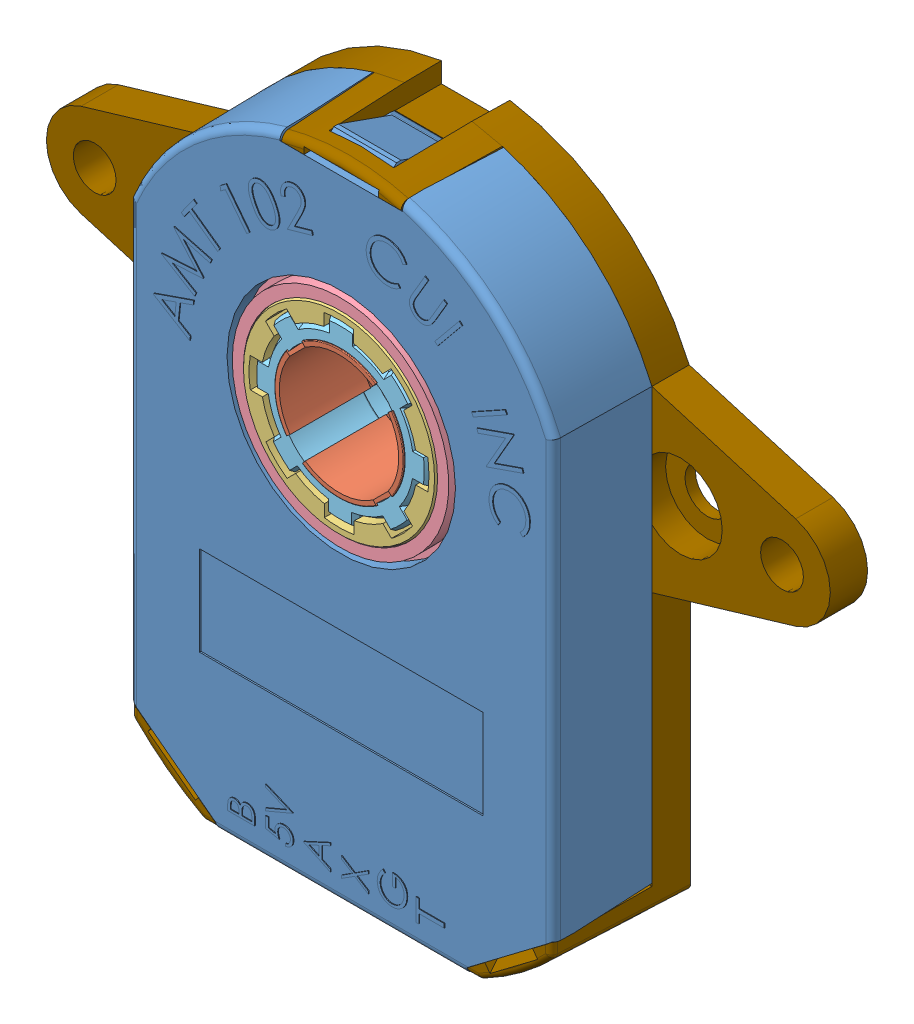
SolidWorks assembly MR2_planetary_shoulder_CUI_INC_cui_amt102-0048-n8000-w, configuration Default. Lengths in mm.
Overall size (52.5 46.23 9.15).
9 component instances, 9 part files, 0 mates.
Components (placement in the parent):
- MR2_planetary_shoulder_CUI_INC_amt-102-top-cover-rev-h-1: MR2_planetary_shoulder_CUI_INC_amt-102-top-cover-rev-h [Default] at (0 0 5.23) x (-1 0 0) z (0 0 -1) size (28.6 43.26 6.55)
- MR2_planetary_shoulder_CUI_INC_amt-sleeve-rev-d(8 mm)-1: MR2_planetary_shoulder_CUI_INC_amt-sleeve-rev-d(8 mm) [Default] at (0 0 -2.42) x (0.999996 0.002864 0) z (0 0 1) size (10.79 10.79 7.8)
- MR2_planetary_shoulder_CUI_INC_amt-hub-top-rev-d1-1: MR2_planetary_shoulder_CUI_INC_amt-hub-top-rev-d1 [Default] at (0 0 2.13) x (0.999996 0.002864 0) z (0 0 1) size (14 14 5.67)
- MR2_planetary_shoulder_CUI_INC_amt-hub-bottom-rev-b-1: MR2_planetary_shoulder_CUI_INC_amt-hub-bottom-rev-b [Default] at (0 0 2.43) x (0.999998 -0.001942 0) z (0 0 1) size (17.3 17.3 3.2)
- MR2_planetary_shoulder_CUI_INC_amt10x-shaft-adaptor-rev-e-1: MR2_planetary_shoulder_CUI_INC_amt10x-shaft-adaptor-rev-e [Default] at (0 0 0.03) x (0.999996 0.002864 0) z (0 0 1) size (11.8 11.8 7.8)
- MR2_planetary_shoulder_CUI_INC_receiver-board-1: MR2_planetary_shoulder_CUI_INC_receiver-board [Default] at (72.2834 -20.351 3.03) x (-1 0 0) z (0 0 -1) size (26.5 26.62 0.41)
- MR2_planetary_shoulder_CUI_INC_rotor-board-rev f-1: MR2_planetary_shoulder_CUI_INC_rotor-board-rev f [Default] at (0 0 2.13) x (0.807874 -0.589355 0) z (0 0 1) size (26 26 0.3)
- MR2_planetary_shoulder_CUI_INC_transmitter-board amt10(amt-102)-1: MR2_planetary_shoulder_CUI_INC_transmitter-board amt10(amt-102) [Default] at (19.1596 -17.1102 1.22) x (-1 0 0) z (0 0 -1) size (26.63 38.43 4.41)
- MR2_planetary_shoulder_CUI_INC_amt-102-wide-base-rev-j-1: MR2_planetary_shoulder_CUI_INC_amt-102-wide-base-rev-j [Default] x (-1 0 0) z (0 0 -1) size (52.5 43.41 9.03)
